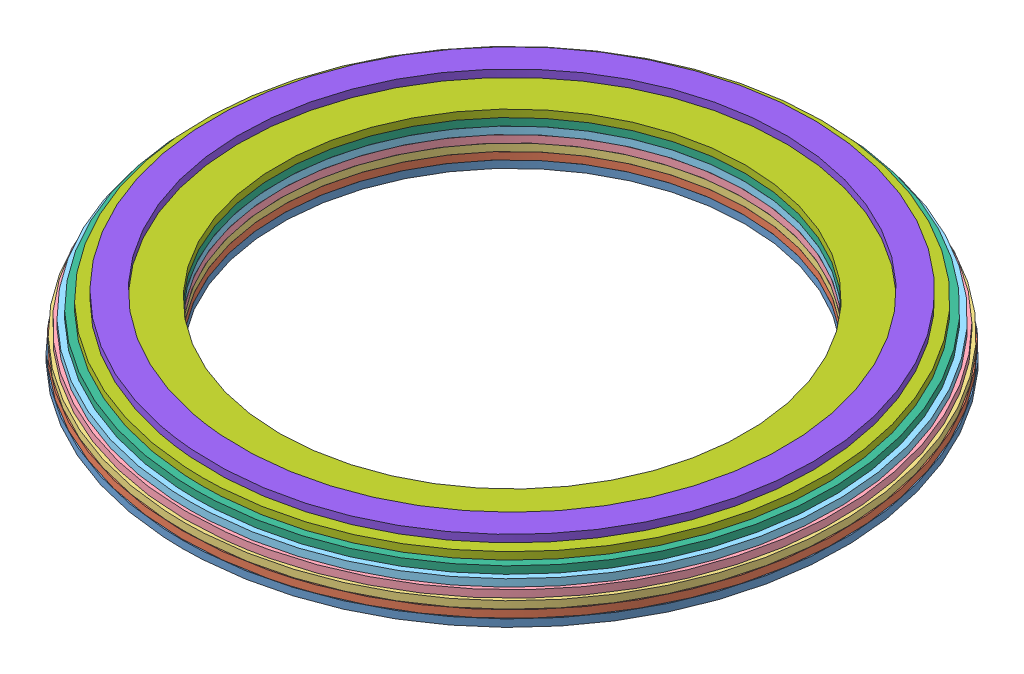
SolidWorks assembly Assem1, configuration Default. Lengths in mm.
Overall size (268.16 19.2 268.16).
8 component instances, 8 part files, 8 mates.
Components (placement in the parent):
- Ring1-1: Ring1 [Default] at (44.9193 119.8244 178.8676) size (215.9 2.4 215.9)
- Ring2-1: Ring2 [Default] at (44.9193 122.2244 178.8676) x (0.957898 0 -0.287109) z (0.287109 0 0.957898) size (215.39 2.4 215.39)
- Ring3-1: Ring3 [Default] at (44.9193 124.6244 178.8676) size (214.88 2.4 214.88)
- Ring4-1: Ring4 [Default] at (44.9193 127.0244 178.8676) x (0.985533 0 -0.169483) z (0.169483 0 0.985533) size (212.85 2.4 212.85)
- Ring5-1: Ring5 [Default] at (44.9193 129.4244 178.8676) size (210.82 2.4 210.82)
- Ring6-1: Ring6 [Default] at (44.9193 131.8244 178.8676) size (207.26 2.4 207.26)
- Ring7-1: Ring7 [Default] at (44.9193 134.2244 178.8676) size (202.69 2.4 202.69)
- Ring8-1: Ring8 [Default] at (44.9193 136.6244 178.8676) x (0.990349 0 0.138597) z (-0.138597 0 0.990349) size (195.58 2.4 195.58)
Mates (geometry in assembly coordinates):
- Coincident2: coincident aligned: circle of Ring1-1; circle of Ring2-1
- Coincident3: coincident aligned: circle of Ring2-1; circle of Ring3-1
- Coincident4: coincident aligned: circle of Ring3-1; circle of Ring4-1
- Coincident5: coincident aligned: circle of Ring4-1; circle of Ring5-1
- Coincident6: coincident aligned: circle of Ring5-1; circle of Ring6-1
- Coincident7: coincident aligned: circle of Ring6-1; circle of Ring7-1
- Coincident8: coincident anti-aligned: plane of Ring7-1 through (44.9193 136.6244 178.8676) normal (0 1 0); plane of Ring8-1 through (44.9193 136.6244 178.8676) normal (0 -1 0)
- Concentric2: concentric aligned: circle of Ring6-1; circle of Ring8-1
